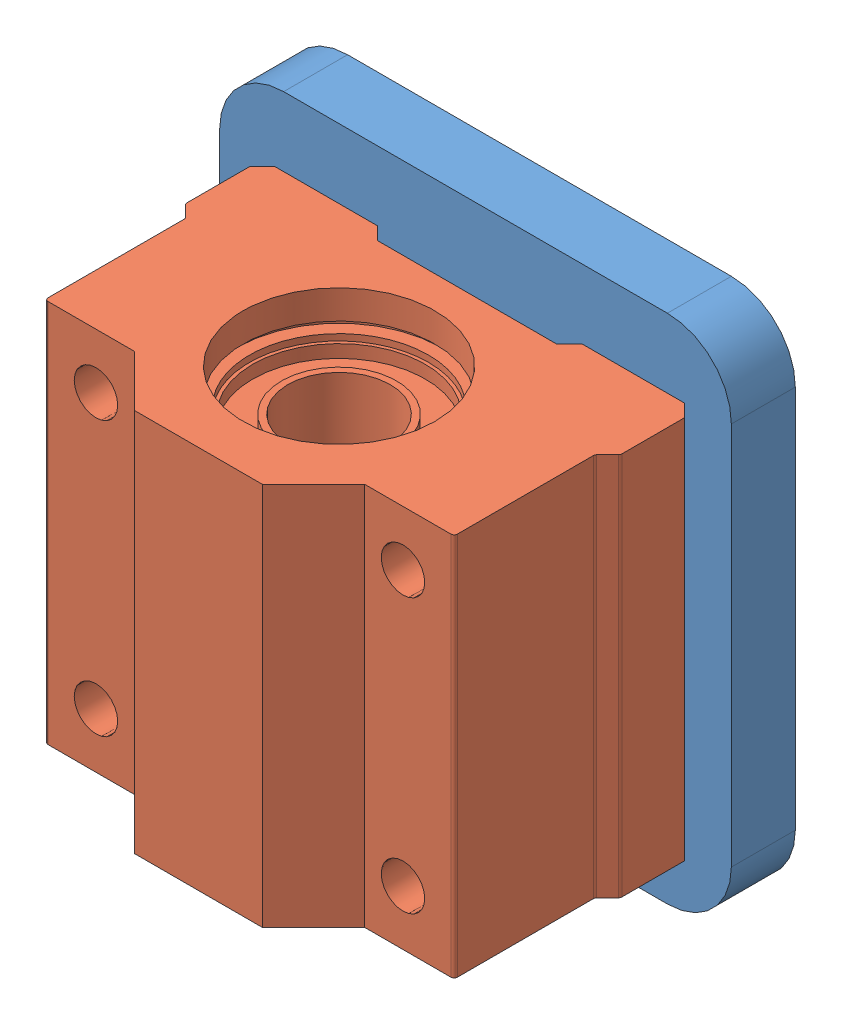
SolidWorks assembly Assem3, configuration Default. Lengths in mm.
Overall size (40 40 27).
2 component instances, 2 part files, 2 mates.
Components (placement in the parent):
- SCUU8_holder-1: SCUU8_holder [Default] at (17.2477 24.6783 24.3964) x (1 0 0) z (0 -1 0) size (40 5 40)
- SCS8UU.stp-1: SCS8UU.stp [Default] at (17.5772 24.2626 41.8964) x (1 0 0) z (0 -1 0) size (34 22 30)
Mates (geometry in assembly coordinates):
- Coincident1: coincident: plane of assembly; plane of assembly; plane of SCUU8_holder-1 through (17.2477 24.6783 29.3964) normal (0 0 1); plane of SCS8UU.stp-1 through (0.5772 24.2626 29.3964) normal (0 0 -1)
- Coincident2: coincident: plane of assembly; plane of assembly; plane of SCUU8_holder-1 through (17.2477 24.6783 29.3964) normal (0 0 1); plane of SCS8UU.stp-1 through (0.5772 24.2626 29.3964) normal (0 0 -1)
